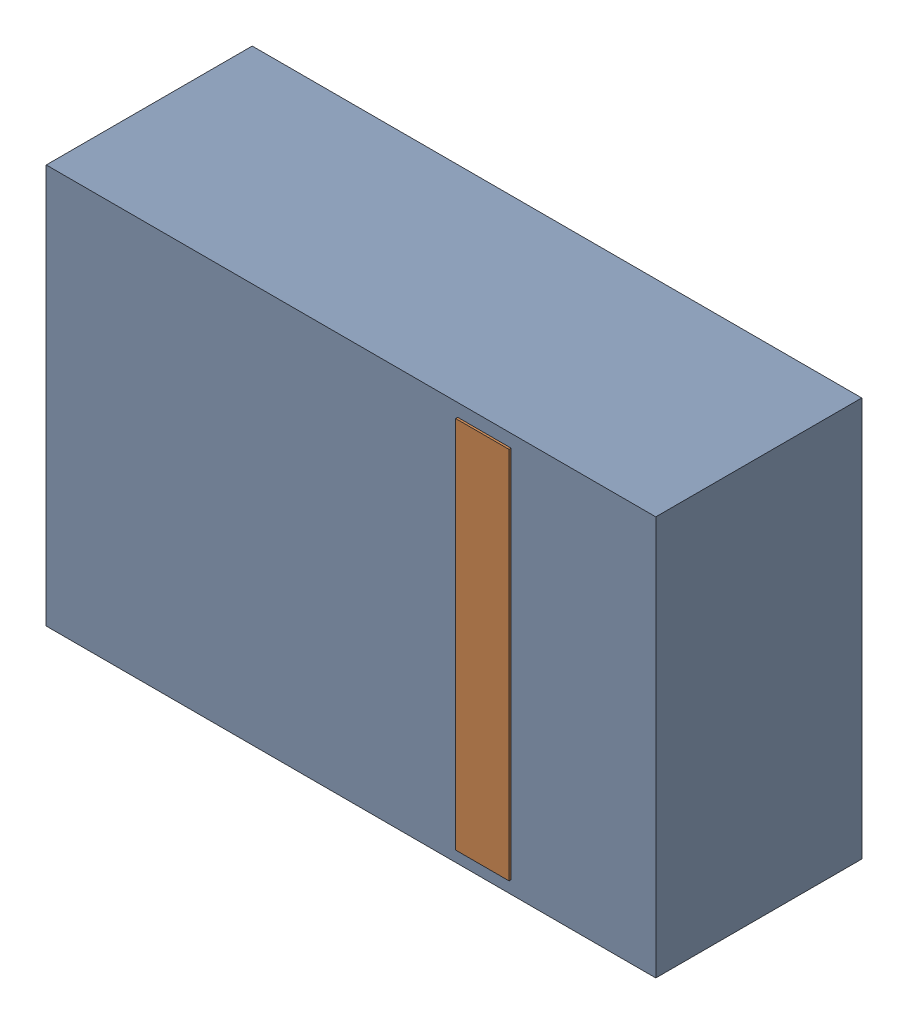
SolidWorks assembly D16, configuration Default. Lengths in mm.
Overall size (2.9 1.9 0.99).
4 component instances, 2 part files, 0 mates.
Components (placement in the parent):
- 905269392-1: 905269392 [Default] at (86.487 72.898 0) size (2.9 1.9 0.98)
  - Extruded_5-1: Extruded_5 [Default] at origin size (2.9 1.9 0.98)
- 905269800-1: 905269800 [Default] at (87.122 72.898 0.95) size (0.25 1.78 0.04)
  - Extruded_6-1: Extruded_6 [Default] at origin size (0.25 1.78 0.04)
